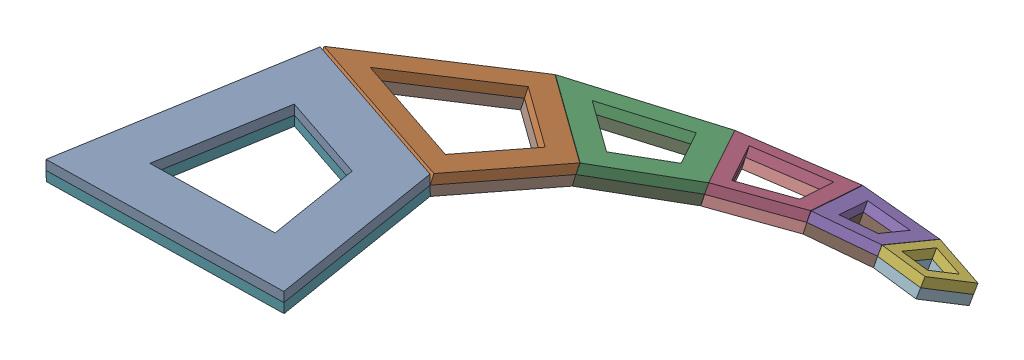
SolidWorks assembly Curling Spiral (Outer Spine)_Assem, configuration Default. Lengths in mm.
Overall size (93.27 32.77 108.71).
12 component instances, 6 part files, 26 mates.
Components (placement in the parent):
- Spiral_1-1: Spiral_1 [Default] at (-16.342 9.2411 59.0905) x (0.999823 0.018827 -0.00003) z (-0.00003 0.003181 0.999995) size (50 2 49.3)
- Spiral_2-1: Spiral_2 [Default] at (-8.0237 9.2409 9.7852) x (0.944377 0.018828 0.328326) z (-0.316587 0.322308 0.892127) size (37.51 2 36.99)
- Spiral_3-1: Spiral_3 [Default] at (9.5808 -2.5641 -21.1663) x (0.788062 0.123615 0.603057) z (-0.60591 0.328862 0.724378) size (28.14 2 27.75)
- Spiral_4-1: Spiral_4 [Default] at (30.0859 -11.1119 -38.4457) x (0.545412 0.224745 0.807474) z (-0.834485 0.235815 0.498022) size (21.11 2 20.82)
- Spiral_5-1: Spiral_5 [Default] at (49.3765 -15.2323 -45.9785) x (0.241163 0.289716 0.926232) z (-0.962882 0.19066 0.191069) size (15.84 2 15.62)
- Spiral_6-1: Spiral_6 [Default] at (65.0529 -17.447 -46.5222) x (-0.088377 0.336256 0.937615) z (-0.98537 0.108197 -0.131681) size (11.88 2 11.72)
- Spiral_1-2: Spiral_1 [Default] at (-16.3044 7.2415 59.0968) x (0.999823 0.018827 -0.00003) z (-0.00003 0.003181 0.999995) size (50 2 49.3)
- Spiral_2-3: Spiral_2 [Default] at (-8.2017 7.348 10.4059) x (0.944377 0.018828 0.328326) z (-0.316587 0.322308 0.892127) size (37.51 2 36.99)
- Spiral_3-3: Spiral_3 [Default] at (9.3633 -4.4366 -20.4982) x (0.788062 0.123615 0.603057) z (-0.60591 0.328862 0.724378) size (28.14 2 27.75)
- Spiral_4-3: Spiral_4 [Default] at (29.9289 -13.0028 -37.8134) x (0.545412 0.224745 0.807474) z (-0.834485 0.235815 0.498022) size (21.11 2 20.82)
- Spiral_5-3: Spiral_5 [Default] at (49.134 -17.1082 -45.3287) x (0.241163 0.289716 0.926232) z (-0.962882 0.19066 0.191069) size (15.84 2 15.62)
- Spiral_6-3: Spiral_6 [Default] at (64.7614 -19.3181 -45.8786) x (-0.088377 0.336256 0.937615) z (-0.98537 0.108197 -0.131681) size (11.88 2 11.72)
Mates (geometry in assembly coordinates):
- Coincident4: coincident anti-aligned: line of Spiral_1-1 through (27.4019 9.9471 22.1015) axis (-0.944377 -0.018828 -0.328326); line of Spiral_2-1 through (-8.0237 9.2409 9.7852) axis (0.944377 0.018828 0.328326)
- Coincident5: coincident: point of Spiral_1-1; point of Spiral_2-1
- Coincident6: coincident anti-aligned: line of Spiral_2-1 through (31.7594 0.9149 -4.1943) axis (-0.788062 -0.123615 -0.603057); line of Spiral_3-1 through (9.5808 -2.5641 -21.1663) axis (0.788062 0.123615 0.603057)
- Coincident7: coincident anti-aligned: line of Spiral_3-1 through (41.6019 -6.3666 -21.3966) axis (-0.545412 -0.224745 -0.807474); line of Spiral_4-1 through (30.0859 -11.1119 -38.4457) axis (0.545412 0.224745 0.807474)
- Coincident8: coincident anti-aligned: line of Spiral_4-1 through (53.1967 -10.643 -31.3063) axis (-0.241163 -0.289716 -0.926232); line of Spiral_5-1 through (49.3765 -15.2323 -45.9785) axis (0.241163 0.289716 0.926232)
- Coincident10: coincident: point of Spiral_2-1; point of Spiral_3-1
- Coincident11: coincident: point of Spiral_3-1; point of Spiral_4-1
- Coincident12: coincident: point of Spiral_4-1; point of Spiral_5-1
- Coincident50: coincident anti-aligned: line of Spiral_1-2 through (27.4019 9.9471 22.1015) axis (-0.944377 -0.018828 -0.328326); line of Spiral_2-3 through (-8.0237 9.2409 9.7852) axis (0.944377 0.018828 0.328326)
- Coincident51: coincident: point of Spiral_1-2; point of Spiral_2-3
- Coincident52: coincident: point of Spiral_2-3; point of Spiral_3-3
- Coincident53: coincident anti-aligned: line of Spiral_2-3 through (31.7594 0.9149 -4.1943) axis (-0.788062 -0.123615 -0.603057); line of Spiral_3-3 through (9.5808 -2.5641 -21.1663) axis (0.788062 0.123615 0.603057)
- Coincident54: coincident anti-aligned: line of Spiral_3-3 through (41.6019 -6.3666 -21.3966) axis (-0.545412 -0.224745 -0.807474); line of Spiral_4-3 through (30.0859 -11.1119 -38.4457) axis (0.545412 0.224745 0.807474)
- Coincident55: coincident: point of Spiral_3-3; point of Spiral_4-3
- Coincident57: coincident anti-aligned: line of Spiral_4-3 through (53.1967 -10.643 -31.3063) axis (-0.241163 -0.289716 -0.926232); line of Spiral_5-3 through (49.3765 -15.2323 -45.9785) axis (0.241163 0.289716 0.926232)
- Coincident58: coincident: point of Spiral_4-3; point of Spiral_5-3
- Coincident59: coincident anti-aligned: line of Spiral_5-3 through (64.0026 -13.4508 -35.3792) axis (0.088377 -0.336256 -0.937615); line of Spiral_6-3 through (65.0529 -17.447 -46.5222) axis (-0.088377 0.336256 0.937615)
- Coincident63: coincident anti-aligned: line of Spiral_5-1 through (64.0026 -13.4508 -35.3792) axis (0.088377 -0.336256 -0.937615); line of Spiral_6-1 through (65.0529 -17.447 -46.5222) axis (-0.088377 0.336256 0.937615)
- Coincident62: coincident: point of Spiral_1-1; point of Spiral_1-2
- Coincident64: coincident: point of Spiral_5-1; point of Spiral_6-1
- Coincident75: coincident: point of Spiral_3-1; point of Spiral_3-3
- Coincident79: coincident: point of Spiral_3-1; point of Spiral_3-3
- Coincident80: coincident: point of Spiral_5-1; point of Spiral_5-3
- Coincident81: coincident: point of Spiral_6-1; point of Spiral_6-3
- Coincident82: coincident: point of Spiral_6-1; point of Spiral_6-3
- Coincident83: coincident: point of Spiral_1-1; point of Spiral_1-2
